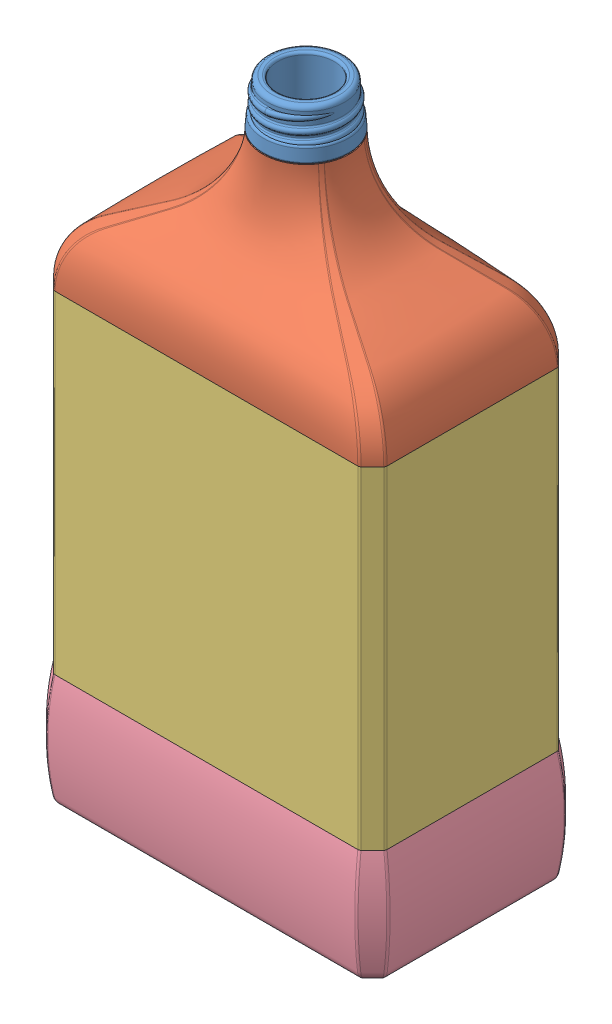
SolidWorks assembly Assemblage Bouteille Carré Droit, configuration Défaut. Lengths in mm.
Overall size (105.96 202.76 64.89).
4 component instances, 4 part files, 9 mates.
Components (placement in the parent):
- Bague couronne A2-1: Bague couronne A2 [Défaut] at origin size (26 14.2 26)
- EP-BC-DR-1: EP-BC-DR [Défaut] at (0 50 0) size (102.25 50 62.78)
- CO-BC-DR-1: CO-BC-DR [Défaut] at (0 -50 0) size (100 100 60)
- JF-BC-DR-DR-1: JF-BC-DR-DR [Défaut] at (0 200 0) size (105.96 39.54 64.89)
Mates (geometry in assembly coordinates):
- Coïncidente3: coincident aligned: plane of EP-BC-DR-1 through (0 50 0) normal (0 0 1); plane of assembly through (0 0 0) normal (0 0 1)
- Coïncidente4: coincident aligned: plane of EP-BC-DR-1 through (0 50 0) normal (1 0 0); plane of assembly through (0 0 0) normal (1 0 0)
- Coïncidente5: coincident aligned: plane of CO-BC-DR-1 through (0 -50 0) normal (0 0 1); plane of assembly through (0 0 0) normal (0 0 1)
- Coïncidente6: coincident aligned: plane of CO-BC-DR-1 through (0 -50 0) normal (1 0 0); plane of assembly through (0 0 0) normal (1 0 0)
- Coïncidente7: coincident aligned: plane of JF-BC-DR-DR-1 through (0 200 0) normal (0 0 1); plane of assembly through (0 0 0) normal (0 0 1)
- Coïncidente8: coincident aligned: plane of JF-BC-DR-DR-1 through (0 200 0) normal (1 0 0); plane of assembly through (0 0 0) normal (1 0 0)
- Coïncidente9: coincident anti-aligned: plane of CO-BC-DR-1 through (0 -150 0) normal (0 -1 0); plane of JF-BC-DR-DR-1 through (0 -150 0) normal (0 1 0)
- Coïncidente10: coincident anti-aligned: plane of EP-BC-DR-1 through (0 -50 0) normal (0 -1 0); plane of CO-BC-DR-1 through (0 -50 0) normal (0 1 0)
- Coïncidente11: coincident anti-aligned: plane of Bague couronne A2-1 through (8.5 0 0) normal (0 -1 0); plane of EP-BC-DR-1 through (0 0 0) normal (0 1 0)
